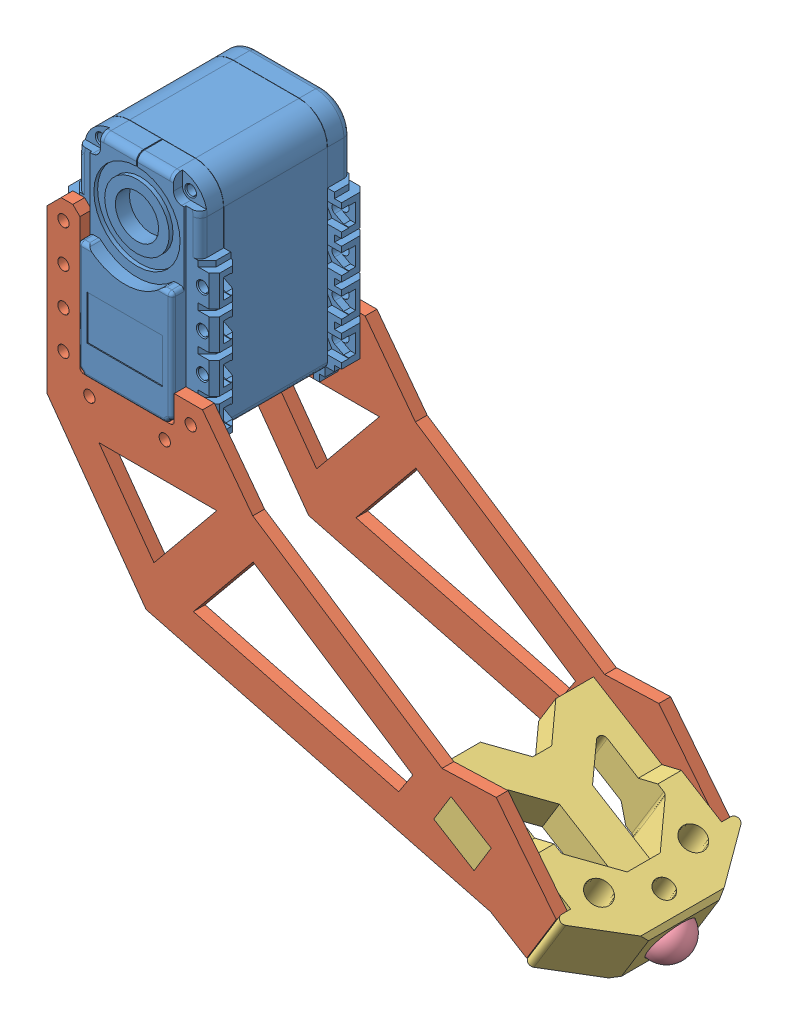
SolidWorks assembly Tibia_right, configuration Default. Lengths in mm.
Overall size (119.5 110.03 38.67).
5 component instances, 4 part files, 12 mates.
Components (placement in the parent):
- ServoBody-1: ServoBody [Default] at origin size (32 50.04 38.67)
- Tibia side plate-1: Tibia side plate [Défaut] at (0.5 -20.25 5.1) x (0 -1 0) z (0 0 -1) size (90.35 108.03 2.5)
- Tibia side plate-2: Tibia side plate [Défaut] at (0.5 -20.25 -29.4) x (0 -1 0) z (0 0 -1) size (90.35 108.03 2.5)
- Foot-1: Foot [Défaut] at (66.4223 -77.6675 -13.4) x (0 0 -1) z (0.521616 0.853181 0) size (37.94 40 13)
- RubberFeet-1: RubberFeet [Default] at (96.4029 -91.8947 -13.4) x (0.521616 0.853181 0) z (0 0 1) size (9.6 4.8 9.6)
Mates (geometry in assembly coordinates):
- Coincident3: coincident anti-aligned: plane of Tibia side plate-2 through (0.5 -20.25 -29.4) normal (0 0 1); plane of Foot-1 through (70.0736 -71.6952 -29.4) normal (0 0 -1)
- Coincident4: coincident anti-aligned: plane of Tibia side plate-2 through (69.2204 -71.1736 -29.399) normal (0.853181 -0.521616 0); plane of Foot-1 through (69.2204 -71.1736 -13.4) normal (-0.853181 0.521616 0)
- Coincident5: coincident anti-aligned: plane of Tibia side plate-2 through (69.2204 -71.1736 -29.399) normal (-0.521616 -0.853181 0); plane of Foot-1 through (70.0736 -71.6952 -13.4) normal (0.521616 0.853181 0)
- Coincident8: coincident anti-aligned: plane of ServoBody-1 through (-14.996 -38.283 2.6) normal (0 0 1); plane of Tibia side plate-1 through (0.5 -20.25 2.6) normal (0 0 -1)
- Coincident9: coincident anti-aligned: plane of ServoBody-1 through (15.996 -38.348 -29.4) normal (0 0 -1); plane of Tibia side plate-2 through (0.5 -20.25 -29.4) normal (0 0 1)
- Concentric7: concentric aligned: cylinder of ServoBody-1 through (-13 -6.5 2.4) axis (0 0 -1) radius 1.1; cylinder of Tibia side plate-1 through (-13 -6.5 2.6) axis (0 0 -1) radius 1.2
- Concentric8: concentric aligned: cylinder of ServoBody-1 through (-13 -30.5 2.4) axis (0 0 -1) radius 1.1; cylinder of Tibia side plate-1 through (-13 -30.5 2.6) axis (0 0 -1) radius 1.2
- Concentric9: concentric aligned: cylinder of ServoBody-1 through (-13 -6.5 -24.4) axis (0 0 -1) radius 1.1; cylinder of Tibia side plate-2 through (-13 -6.5 -31.9) axis (0 0 -1) radius 1.2
- Concentric10: concentric aligned: cylinder of ServoBody-1 through (-13 -30.5 -27.4) axis (0 0 -1) radius 1.1; cylinder of Tibia side plate-2 through (-13 -30.5 -31.9) axis (0 0 -1) radius 1.2
- Coincident10: coordinate: point of ServoBody-1; point of assembly
- Coincident11: coincident: plane of Foot-1 through (96.4029 -91.8947 -13.4) normal (0.853181 -0.521616 0); plane of RubberFeet-1 through (93.8991 -95.99 -13.4) normal (-0.853181 0.521616 0)
- Concentric11: concentric anti-aligned: circle of Foot-1; circle of RubberFeet-1
